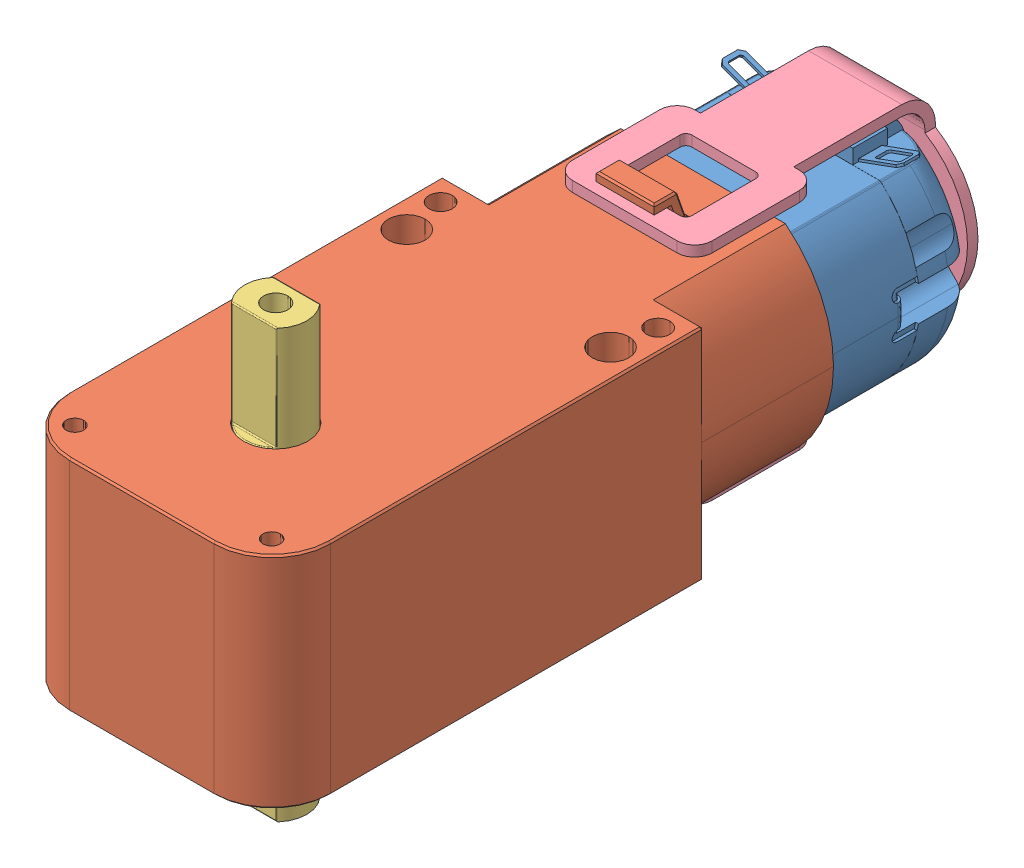
SolidWorks assembly Mini Gear DC Motor 6 V Yellow, configuration Default. Lengths in mm.
Overall size (22.4 36.71 65.5).
5 component instances, 4 part files, 0 mates.
Components (placement in the parent):
- Mini Gear DC Motor 6 V Yellow.STEP-1: Mini Gear DC Motor 6 V Yellow.STEP [Default] at origin size (22.4 36.71 65.5)
  - dc motor.stp.STEP-1: dc motor.stp.STEP [Default] at (13.3606 26.0064 34.2186) size (20.08 18.68 36.5)
  - Nody.STEP-1: Nody.STEP [Default] at (24.2594 15.6964 33.7186) x (-1 0 0) z (0 0 -1) size (22.4 22.91 48.2)
  - Axe.STEP-1: Axe.STEP [Default] at (13.0594 6.7714 59.2186) x (-1 0 0) z (0 0 -1) size (5.35 36.71 5.35)
  - Belt.STEP-1: Belt.STEP [Default] at (21.0106 0 -1.0745) x (0 0 1) z (-1 0 0) size (22.68 19.3 15.3)
